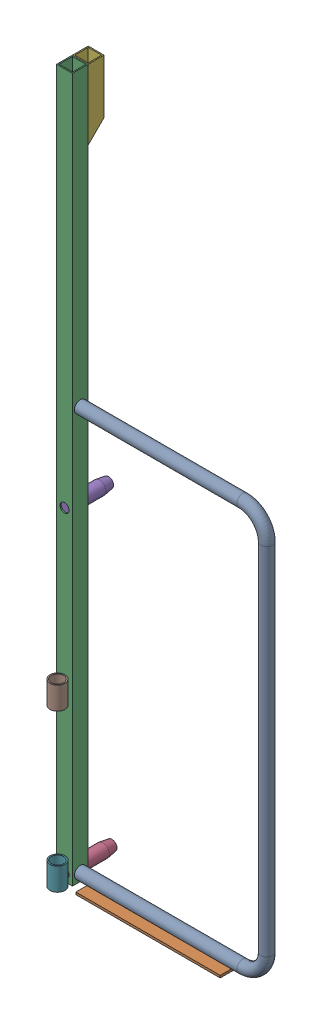
SolidWorks assembly FE-00002-11_, configuration Default. Lengths in mm.
Overall size (585.85 1981.2 175.51).
8 component instances, 7 part files, 0 mates.
Components (placement in the parent):
- FE-00002-06_-1: FE-00002-06_ [Default] at origin size (541.4 1168.46 33.4)
- FE-00002-07_-1: FE-00002-07_ [Default] at (-512.5043 -164.7728 18.6687) x (1 0 0) z (0 -1 0) size (406.4 76.2 6.35)
- FE-00002-05_-1: FE-00002-05_ [Default] at (-595.693 -171.1228 9.0928) x (0 0 1) z (0 1 0) size (44.45 44.45 1981.2)
- FE-00002-01_-1: FE-00002-01_ [Default] at (-590.5987 -161.4938 -111.125) size (36.51 36.51 130.18)
- FE-00002-02_-1: FE-00002-02_ [Default] at (-590.5987 727.5062 -101.6) size (36.51 36.51 120.65)
- FE-00002-03_-1: FE-00002-03_ [Default] at (-587.0632 1613.2272 -39.9571) x (1 0 0) z (0 1 0) size (44.45 44.45 196.85)
- FE-00002-9_REV2_-1: FE-00002-9_REV2_ [Default] at (-594.2944 -171.1228 43.307) size (42.16 63.5 42.16)
- FE-00002-9_REV2_-2: FE-00002-9_REV2_ [Default] at (-594.2944 270.2022 43.307) size (42.16 63.5 42.16)
